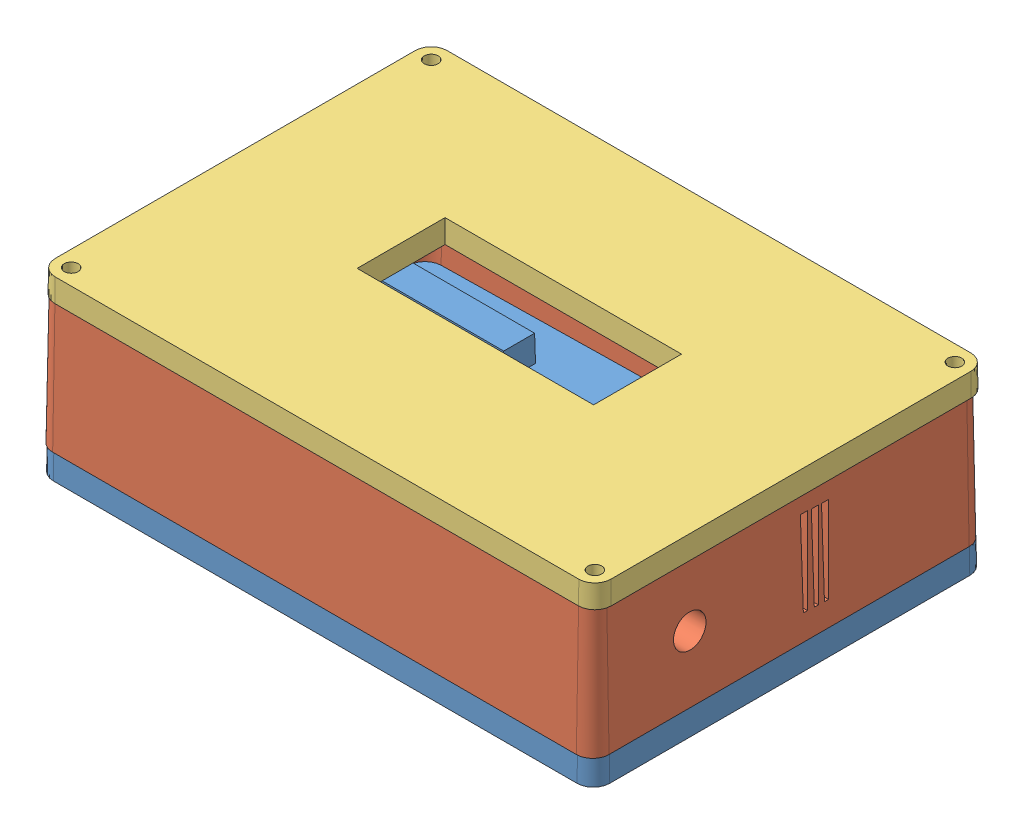
SolidWorks assembly Design_with_draft, configuration Default. Lengths in mm.
Overall size (170.57 54.21 120.75).
3 component instances, 3 part files, 0 mates.
Components (placement in the parent):
- Base_with_draft-1: Base_with_draft [Default] at (58.7804 74.8634 142.3678) size (170 16 120)
- Wall_with_draft-1: Wall_with_draft [Default] at (59.0333 82.8532 142.832) size (170.57 40 120.57)
- Lid_with_draft-1: Lid_with_draft [Default] at (59.2597 122.0778 142.4068) size (170 7 120)
